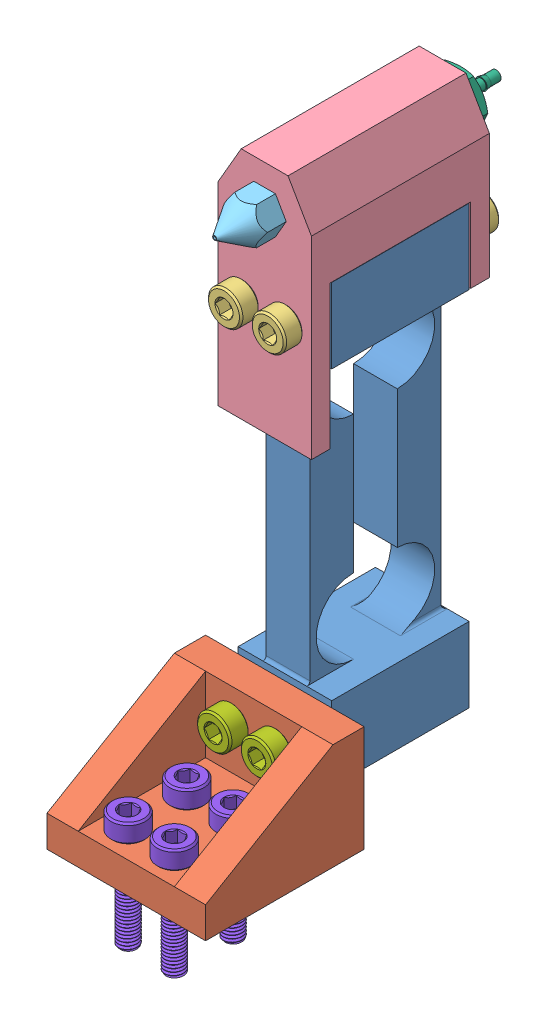
SolidWorks assembly SUB_Load Cell Mounting Assembly, configuration Default. Lengths in mm.
Overall size (25.4 101.65 59.22).
15 component instances, 8 part files, 42 mates.
Components (placement in the parent):
- E05_Load Cell-1: E05_Load Cell [Default] at (-1.4723 11.6667 38.7166) x (0 1 0) z (-1 0 0) size (70 22 15)
- M23_Load Cell Bracket-1: M23_Load Cell Bracket [Default] at (-6.6723 5.6667 64.1166) size (25.4 17 25.4)
- M44_91292A113_18-8 Stainless Steel Socket Head Screw-1: M44_91292A113_18-8 Stainless Steel Socket Head Screw [91292A113] at (9.5277 75.6667 31.9666) x (-0.866025 -0.5 0) z (0 0 -1) size (5.5 5.5 13.21)
- M44_91292A113_18-8 Stainless Steel Socket Head Screw-2: M44_91292A113_18-8 Stainless Steel Socket Head Screw [91292A113] at (2.5277 75.6667 31.9666) x (0 -1 0) z (0 0 -1) size (5.5 5.5 13.21)
- M44_91292A113_18-8 Stainless Steel Socket Head Screw-3: M44_91292A113_18-8 Stainless Steel Socket Head Screw [91292A113] at (9.5277 75.6667 23.4666) x (0.866025 -0.5 0) z (0 0 1) size (5.5 5.5 13.21)
- M44_91292A113_18-8 Stainless Steel Socket Head Screw-4: M44_91292A113_18-8 Stainless Steel Socket Head Screw [91292A113] at (2.5277 75.6667 23.4666) x (-0.866025 -0.5 0) z (0 0 1) size (5.5 5.5 13.21)
- M24_Nozzle Mount-1: M24_Nozzle Mount [Default] at (6.0277 89.7167 13.4666) size (15 37.5 28.5)
- M20_Creality Brass Nozzle-1: M20_Creality Brass Nozzle [Default] at (6.0277 89.7167 49.9666) x (0.866025 0.5 0) z (0 0 1) size (6 7.32 13)
- M21_5058K956_ALUMINUM LOW-PRESSURE BARBED TUBE FITTING-1: M21_5058K956_ALUMINUM LOW-PRESSURE BARBED TUBE FITTING [5058K956] at (6.0277 89.7167 12.4348) x (0 0 -1) z (0 1 0) size (15.08 9.17 7.94)
- M41_91292A801_18-8 Stainless Steel Socket Head Screw-1: M41_91292A801_18-8 Stainless Steel Socket Head Screw [91292A801] at (2.5277 17.6667 34.2166) x (0.866025 0.5 0) z (0 0 1) size (5.5 5.5 25.38)
- M41_91292A801_18-8 Stainless Steel Socket Head Screw-2: M41_91292A801_18-8 Stainless Steel Socket Head Screw [91292A801] at (9.5277 17.6667 34.2166) x (0.866025 0.5 0) z (0 0 1) size (5.5 5.5 25.38)
- M25_91292A115_18-8 Stainless Steel Socket Head Screw-1: M25_91292A115_18-8 Stainless Steel Socket Head Screw [91292A115] at (2.3277 -5.3333 60.1166) x (0.866025 0 0.5) z (0 -1 0) size (5.5 5.5 19.25)
- M25_91292A115_18-8 Stainless Steel Socket Head Screw-2: M25_91292A115_18-8 Stainless Steel Socket Head Screw [91292A115] at (9.7277 -5.3333 50.7166) x (0.866025 0 0.5) z (0 -1 0) size (5.5 5.5 19.25)
- M25_91292A115_18-8 Stainless Steel Socket Head Screw-3: M25_91292A115_18-8 Stainless Steel Socket Head Screw [91292A115] at (9.7277 -5.3333 60.1166) x (0 0 1) z (0 -1 0) size (5.5 5.5 19.25)
- M25_91292A115_18-8 Stainless Steel Socket Head Screw-4: M25_91292A115_18-8 Stainless Steel Socket Head Screw [91292A115] at (2.3277 -5.3333 50.7166) x (0.866025 0 0.5) z (0 -1 0) size (5.5 5.5 19.25)
Mates (geometry in assembly coordinates):
- Coincident20: coincident anti-aligned: plane of E5_Load Cell-1 through (-1.4723 11.6667 38.7166) normal (0 0 1); plane of Load Cell Bracket-1 through (18.7277 22.6667 38.7166) normal (0 0 -1)
- Concentric44: concentric aligned: cylinder of E5_Load Cell-1 through (9.5277 75.6667 16.7166) axis (0 0 -1) radius 1.25; cylinder of M24_Nozzle Mount NEW-1 through (9.5277 75.6667 41.9666) axis (0 0 -1) radius 1.55
- Concentric45: concentric aligned: cylinder of E5_Load Cell-1 through (2.5277 75.6667 16.7166) axis (0 0 -1) radius 1.25; cylinder of M24_Nozzle Mount NEW-1 through (2.5277 75.6667 41.9666) axis (0 0 -1) radius 1.55
- Width6: width anti-aligned: plane of M24_Nozzle Mount NEW-1 through (6.0277 58.7167 38.9666) normal (0 0 -1); plane of E5_Load Cell-1 through (6.0277 69.7167 16.4666) normal (0 0 1); plane of M24_Nozzle Mount NEW-1 through (-1.4723 11.6667 38.7166) normal (0 0 1); plane of E5_Load Cell-1 through (-1.4723 11.6667 16.7166) normal (0 0 -1)
- Coincident45: coincident: plane of 91292A113_18-8 Stainless Steel Socket Head Screw-4 through (2.5277 75.6667 13.4666) normal (0 0 1); plane of M24_Nozzle Mount NEW-1 through (6.0277 89.7167 13.4666) normal (0 0 -1)
- Coincident46: coincident: plane of 91292A113_18-8 Stainless Steel Socket Head Screw-3 through (-7.9982 86.5205 13.4666) normal (0 0 1); plane of M24_Nozzle Mount NEW-1 through (6.0277 89.7167 13.4666) normal (0 0 -1)
- Concentric46: concentric anti-aligned: cylinder of M24_Nozzle Mount NEW-1 through (6.0277 89.7167 13.4666) axis (0 0 -1) radius 2.5; cylinder of M20_Creality Brass Nozzle-1 through (6.0277 89.7167 49.9666) axis (0 0 1) radius 3
- Coincident47: coincident anti-aligned: plane of M24_Nozzle Mount NEW-1 through (6.0277 89.7167 41.9666) normal (0 0 1); plane of M20_Creality Brass Nozzle-1 through (4.2957 92.7167 41.9666) normal (0 0 -1)
- Parallel14: parallel anti-aligned: plane of M24_Nozzle Mount NEW-1 through (6.0277 58.7167 13.4666) normal (0 -1 0); plane of M20_Creality Brass Nozzle-1 through (7.7598 92.7167 36.9666) normal (0 1 0)
- Concentric47: concentric anti-aligned: cylinder of M24_Nozzle Mount NEW-1 through (6.0277 89.7167 13.4666) axis (0 0 -1) radius 2.5; cylinder of M21_5058K956_ALUMINUM LOW-PRESSURE BARBED TUBE FITTING-1 through (6.0277 89.7167 4.9814) axis (0 0 1) radius 3
- Coincident49: coincident anti-aligned: plane of M24_Nozzle Mount NEW-1 through (6.0277 89.7167 13.4666) normal (0 0 -1); plane of M21_5058K956_ALUMINUM LOW-PRESSURE BARBED TUBE FITTING-1 through (-0.8464 93.6854 13.4666) normal (0 0 1)
- Parallel15: parallel anti-aligned: plane of M24_Nozzle Mount NEW-1 through (6.0277 69.7167 13.4666) normal (0 -1 0); plane of M21_5058K956_ALUMINUM LOW-PRESSURE BARBED TUBE FITTING-1 through (3.7363 93.6854 13.4666) normal (0 1 0)
- Concentric48: concentric aligned: cylinder of M23_Load Cell Bracket-1 through (2.5277 17.6667 64.1176) axis (0 0 -1) radius 1.55; cylinder of M41_91292A801_18-8 Stainless Steel Socket Head Screw-1 through (2.5277 17.6667 21.7166) axis (0 0 -1) radius 2.75
- Coincident50: coincident anti-aligned: plane of M23_Load Cell Bracket-1 through (18.7277 10.6667 43.7166) normal (0 0 1); plane of M41_91292A801_18-8 Stainless Steel Socket Head Screw-1 through (0.2652 16.3604 43.7166) normal (0 0 -1)
- Parallel16: parallel aligned: plane of M23_Load Cell Bracket-1 through (18.7277 22.6667 43.7166) normal (0 1 0); plane of M41_91292A801_18-8 Stainless Steel Socket Head Screw-1 through (1.806 16.4167 44.8416) normal (0 1 0)
- Concentric49: concentric aligned: cylinder of E5_Load Cell-1 through (2.5277 17.6667 16.7166) axis (0 0 -1) radius 1.25; cylinder of M23_Load Cell Bracket-1 through (2.5277 17.6667 64.1176) axis (0 0 -1) radius 1.55
- Concentric50: concentric aligned: cylinder of E5_Load Cell-1 through (9.5277 17.6667 16.7166) axis (0 0 -1) radius 1.25; cylinder of M23_Load Cell Bracket-1 through (9.5277 17.6667 64.1176) axis (0 0 -1) radius 1.55
- Concentric51: concentric aligned: cylinder of M23_Load Cell Bracket-1 through (9.5277 17.6667 64.1176) axis (0 0 -1) radius 1.55; cylinder of M41_91292A801_18-8 Stainless Steel Socket Head Screw-2 through (9.5277 17.6667 21.7166) axis (0 0 -1) radius 2.75
- Coincident52: coincident anti-aligned: plane of M23_Load Cell Bracket-1 through (18.7277 10.6667 43.7166) normal (0 0 1); plane of M41_91292A801_18-8 Stainless Steel Socket Head Screw-2 through (7.2652 16.3604 43.7166) normal (0 0 -1)
- Parallel17: parallel aligned: plane of M23_Load Cell Bracket-1 through (18.7277 22.6667 43.7166) normal (0 1 0); plane of M41_91292A801_18-8 Stainless Steel Socket Head Screw-2 through (8.806 16.4167 44.8416) normal (0 1 0)
- Concentric52: concentric anti-aligned: cylinder of M23_Load Cell Bracket-1 through (2.3277 5.6657 60.1166) axis (0 1 0) radius 1.55; cylinder of M25_91292A115_18-8 Stainless Steel Socket Head Screw-1 through (2.3277 13.6667 60.1166) axis (0 -1 0) radius 2.75
- Coincident53: coincident anti-aligned: plane of M23_Load Cell Bracket-1 through (18.7277 10.6667 64.1166) normal (0 1 0); plane of M25_91292A115_18-8 Stainless Steel Socket Head Screw-1 through (2.3277 10.6667 60.1166) normal (0 -1 0)
- Parallel18: parallel aligned: plane of M23_Load Cell Bracket-1 through (18.7277 5.6667 64.1166) normal (0 0 1); plane of M25_91292A115_18-8 Stainless Steel Socket Head Screw-1 through (3.0494 11.7917 58.8666) normal (0 0 1)
- Concentric53: concentric anti-aligned: cylinder of M23_Load Cell Bracket-1 through (2.3277 5.6657 50.7166) axis (0 1 0) radius 1.55; cylinder of M25_91292A115_18-8 Stainless Steel Socket Head Screw-4 through (2.3277 13.6667 50.7166) axis (0 -1 0) radius 2.75
- Coincident55: coincident anti-aligned: plane of M23_Load Cell Bracket-1 through (18.7277 10.6667 64.1166) normal (0 1 0); plane of M25_91292A115_18-8 Stainless Steel Socket Head Screw-4 through (2.3277 10.6667 50.7166) normal (0 -1 0)
- Parallel19: parallel aligned: plane of M23_Load Cell Bracket-1 through (18.7277 5.6667 64.1166) normal (0 0 1); plane of M25_91292A115_18-8 Stainless Steel Socket Head Screw-4 through (3.0494 11.7917 49.4666) normal (0 0 1)
- Concentric54: concentric anti-aligned: cylinder of M23_Load Cell Bracket-1 through (9.7277 5.6657 50.7166) axis (0 1 0) radius 1.55; cylinder of M25_91292A115_18-8 Stainless Steel Socket Head Screw-2 through (9.7277 13.6667 50.7166) axis (0 -1 0) radius 2.75
- Coincident57: coincident anti-aligned: plane of M23_Load Cell Bracket-1 through (18.7277 10.6667 64.1166) normal (0 1 0); plane of M25_91292A115_18-8 Stainless Steel Socket Head Screw-2 through (9.7277 10.6667 50.7166) normal (0 -1 0)
- Parallel20: parallel aligned: plane of M23_Load Cell Bracket-1 through (18.7277 5.6667 64.1166) normal (0 0 1); plane of M25_91292A115_18-8 Stainless Steel Socket Head Screw-2 through (10.4494 11.7917 49.4666) normal (0 0 1)
- Concentric56: concentric anti-aligned: cylinder of M23_Load Cell Bracket-1 through (9.7277 5.6657 60.1166) axis (0 1 0) radius 1.55; cylinder of M25_91292A115_18-8 Stainless Steel Socket Head Screw-3 through (9.7277 13.6667 60.1166) axis (0 -1 0) radius 2.75
- Coincident59: coincident anti-aligned: plane of M23_Load Cell Bracket-1 through (18.7277 10.6667 64.1166) normal (0 1 0); plane of M25_91292A115_18-8 Stainless Steel Socket Head Screw-3 through (9.7277 10.6667 60.1166) normal (0 -1 0)
- Parallel21: parallel aligned: plane of M23_Load Cell Bracket-1 through (18.7277 5.6667 64.1166) normal (0 0 1); plane of M25_91292A115_18-8 Stainless Steel Socket Head Screw-3 through (10.4494 11.7917 58.8666) normal (0 0 1)
- Concentric57: concentric aligned: cylinder of M44_91292A113_18-8 Stainless Steel Socket Head Screw-2 through (2.5277 75.6667 44.9666) axis (0 0 -1) radius 2.75; cylinder of M24_Nozzle Mount-1 through (2.5277 75.6667 41.9666) axis (0 0 -1) radius 1.55
- Concentric58: concentric aligned: cylinder of M44_91292A113_18-8 Stainless Steel Socket Head Screw-1 through (9.5277 75.6667 44.9666) axis (0 0 -1) radius 2.75; cylinder of M24_Nozzle Mount-1 through (9.5277 75.6667 41.9666) axis (0 0 -1) radius 1.55
- Coincident60: coincident anti-aligned: plane of M44_91292A113_18-8 Stainless Steel Socket Head Screw-1 through (9.5277 75.6667 41.9666) normal (0 0 -1); plane of M24_Nozzle Mount-1 through (6.0277 89.7167 41.9666) normal (0 0 1)
- Coincident61: coincident anti-aligned: plane of M44_91292A113_18-8 Stainless Steel Socket Head Screw-2 through (2.5277 75.6667 41.9666) normal (0 0 -1); plane of M24_Nozzle Mount-1 through (6.0277 89.7167 41.9666) normal (0 0 1)
- Parallel22: parallel anti-aligned: plane of M44_91292A113_18-8 Stainless Steel Socket Head Screw-2 through (1.806 74.4167 43.0916) normal (0 1 0); plane of M24_Nozzle Mount-1 through (6.0277 58.7167 13.4666) normal (0 -1 0)
- Parallel23: parallel aligned: plane of M44_91292A113_18-8 Stainless Steel Socket Head Screw-1 through (10.2494 76.9167 43.0916) normal (0 -1 0); plane of M24_Nozzle Mount-1 through (6.0277 58.7167 13.4666) normal (0 -1 0)
- Concentric59: concentric: cylinder of M44_91292A113_18-8 Stainless Steel Socket Head Screw-4 through (2.5277 75.6667 10.4666) axis (0 0 1) radius 2.75; cylinder of M24_Nozzle Mount-1 through (2.5277 75.6667 41.9666) axis (0 0 -1) radius 1.55
- Parallel24: parallel aligned: plane of M44_91292A113_18-8 Stainless Steel Socket Head Screw-4 through (1.806 76.9167 12.3416) normal (0 -1 0); plane of M24_Nozzle Mount-1 through (6.0277 69.7167 13.4666) normal (0 -1 0)
- Parallel25: parallel: plane of M44_91292A113_18-8 Stainless Steel Socket Head Screw-3 through (-8.7199 87.7705 12.3416) normal (0 -1 0); plane of M24_Nozzle Mount-1 through (6.0277 69.7167 13.4666) normal (0 -1 0)
- Concentric60: concentric anti-aligned: cylinder of M44_91292A113_18-8 Stainless Steel Socket Head Screw-3 through (9.5277 75.6667 10.4666) axis (0 0 1) radius 2.75; cylinder of M24_Nozzle Mount-1 through (9.5277 75.6667 41.9666) axis (0 0 -1) radius 1.55
